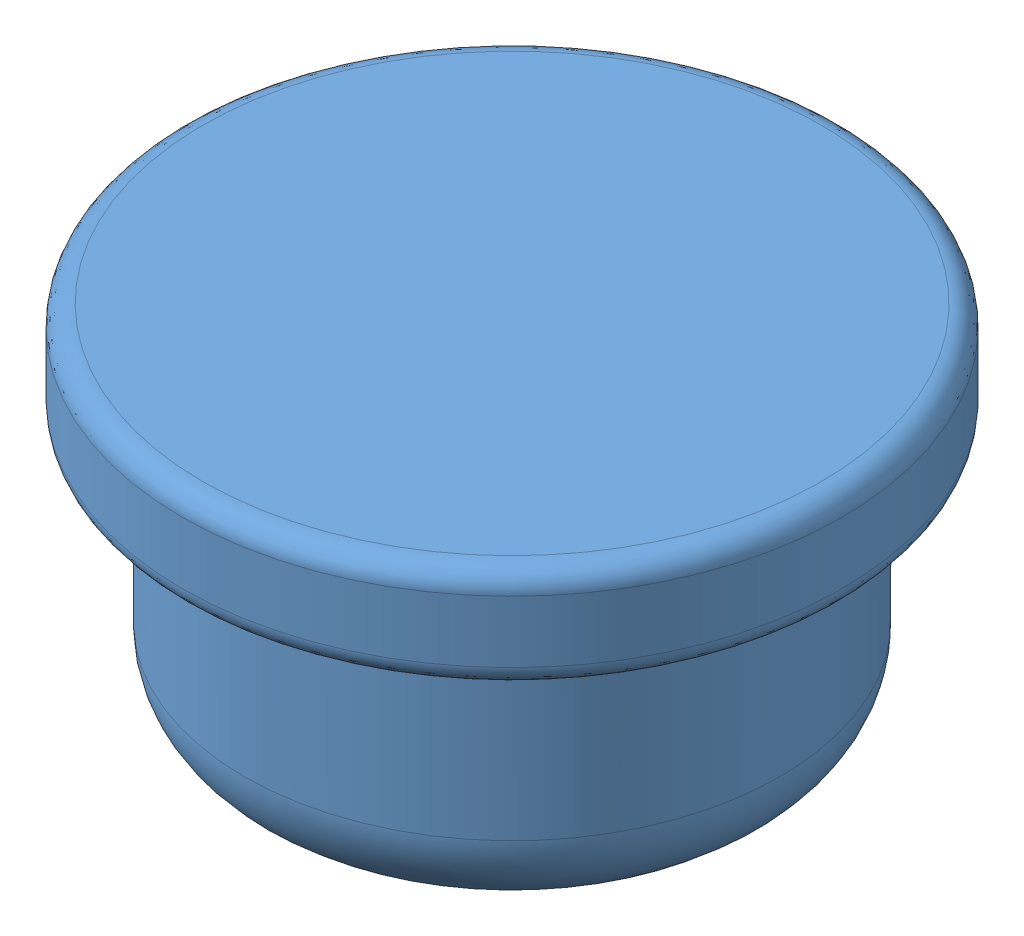
SolidWorks assembly Assem1, configuration Default. Lengths in mm.
Overall size (16 11.27 16).
2 component instances, 2 part files, 1 mates.
Components (placement in the parent):
- CY-8H-BODY-1: CY-8H-BODY [Default] at (5.6232 2.4642 13.5088) size (16 8.7 16)
- CY-8H-TRANSFER BALL-1: CY-8H-TRANSFER BALL [Default] at (5.3245 3.8962 13.476) size (8 8 8)
Mates (geometry in assembly coordinates):
- Lock1: lock: unknown of CY-8H-BODY-1; unknown of CY-8H-TRANSFER BALL-1
